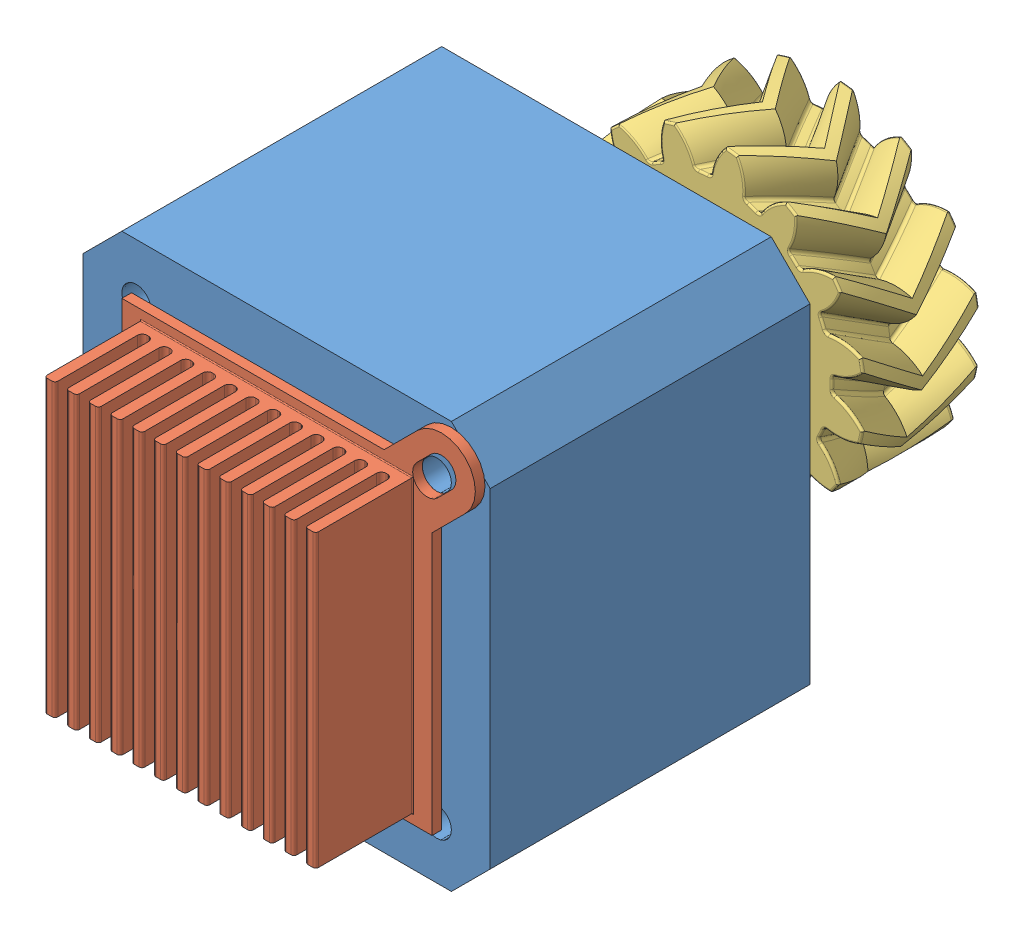
SolidWorks assembly 4.2 MotorAssembly, configuration Domyślna. Lengths in mm.
Overall size (42 42 67.27).
3 component instances, 3 part files, 6 mates.
Components (placement in the parent):
- 2.2.1 Nema 17 x 33-1: 2.2.1 Nema 17 x 33 [Default] at origin size (42 42 56.05)
- 3.2.2 radiator-1: 3.2.2 radiator [Domyślna] at (-0.0002 -0.0002 33) x (0 1 0) z (1 0 0) size (40.94 11 40.94)
- 4.2.2 ISO - LH Helical gear 1.5M 15T 37HA 20PA 6FW ---15A75H50L8.0N-1: 4.2.2 ISO - LH Helical gear 1.5M 15T 37HA 20PA 6FW ---15A75H50L8.0N [ISO - LH Helical gear 1.5M 15T 37HA 20PA 6FW ---15A75H50L8.0N] at (0 0 -23.05) x (0 0 1) z (-0.949504 0.313755 0) size (12.44 31.23 31.24)
Mates (geometry in assembly coordinates):
- Wspólnie17: coincident anti-aligned: plane of 2.2.1 Nema 17 x 33-1 through (0 0 33) normal (0 0 1); plane of 3.2.2 radiator-1 through (-0.0002 -0.0002 33) normal (0 0 -1)
- Koncentryczne22: concentric anti-aligned: cylinder of 2.2.1 Nema 17 x 33-1 through (-15.5 -15.5 33) axis (0 0 -1) radius 1.5; cylinder of 3.2.2 radiator-1 through (-15.5 -15.5 33) axis (0 0 1) radius 1.5
- Koncentryczne23: concentric anti-aligned: cylinder of 2.2.1 Nema 17 x 33-1 through (15.5 15.5 33) axis (0 0 -1) radius 1.5; cylinder of 3.2.2 radiator-1 through (15.4996 15.4996 33) axis (0 0 1) radius 1.5
- Wspólnie18: coordinate: point of 2.2.1 Nema 17 x 33-1; point of assembly
- Wspólnie19: coincident aligned: plane of 2.2.1 Nema 17 x 33-1 through (0 0 -23.05) normal (0 0 -1); plane of 4.2.2 ISO - LH Helical gear 1.5M 15T 37HA 20PA 6FW ---15A75H50L8.0N-1 through (0 0 -23.05) normal (0 0 -1)
- Koncentryczne25: concentric anti-aligned: cylinder of 2.2.1 Nema 17 x 33-1 through (0 0 -23.05) axis (0 0 1) radius 2.5; cylinder of 4.2.2 ISO - LH Helical gear 1.5M 15T 37HA 20PA 6FW ---15A75H50L8.0N-1 through (0 0 39.45) axis (0 0 -1) radius 2.5
